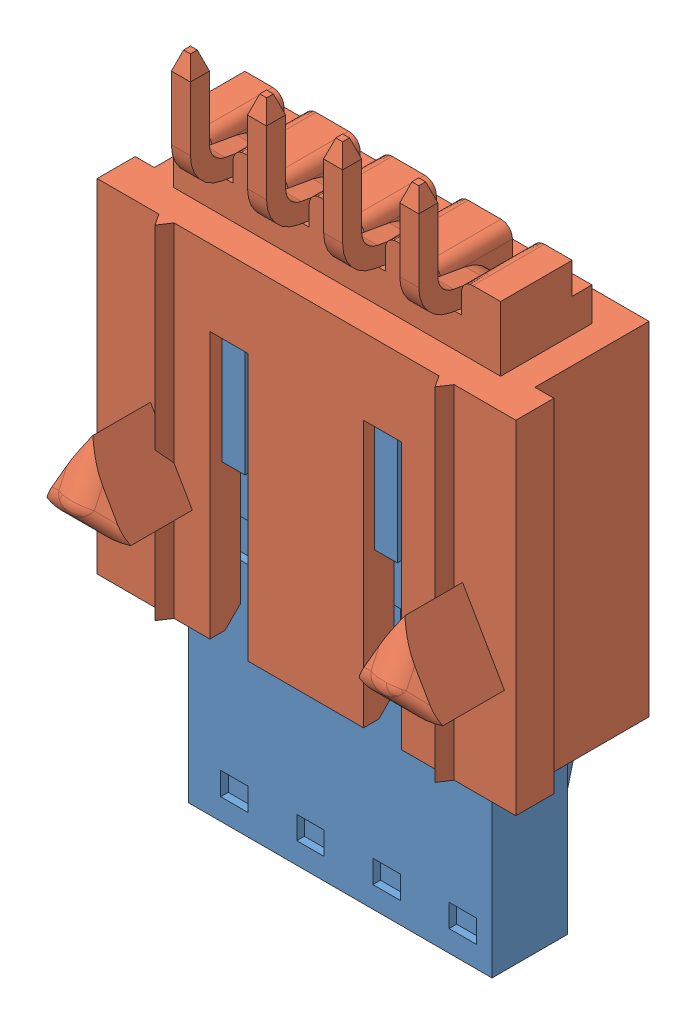
SolidWorks assembly Assem1, configuration Default. Lengths in mm.
Overall size (13.97 23.05 9.38).
2 component instances, 2 part files, 0 mates.
Components (placement in the parent):
- 050579404-1: 050579404 [Default] at (10.5103 8.967 9.4174) size (10.13 15.24 6.45)
- 015913044-2: 015913044 [Default] at (10.5831 13.3435 9.3307) x (-1 0 0) z (0 -1 0) size (13.97 9.35 16.76)
